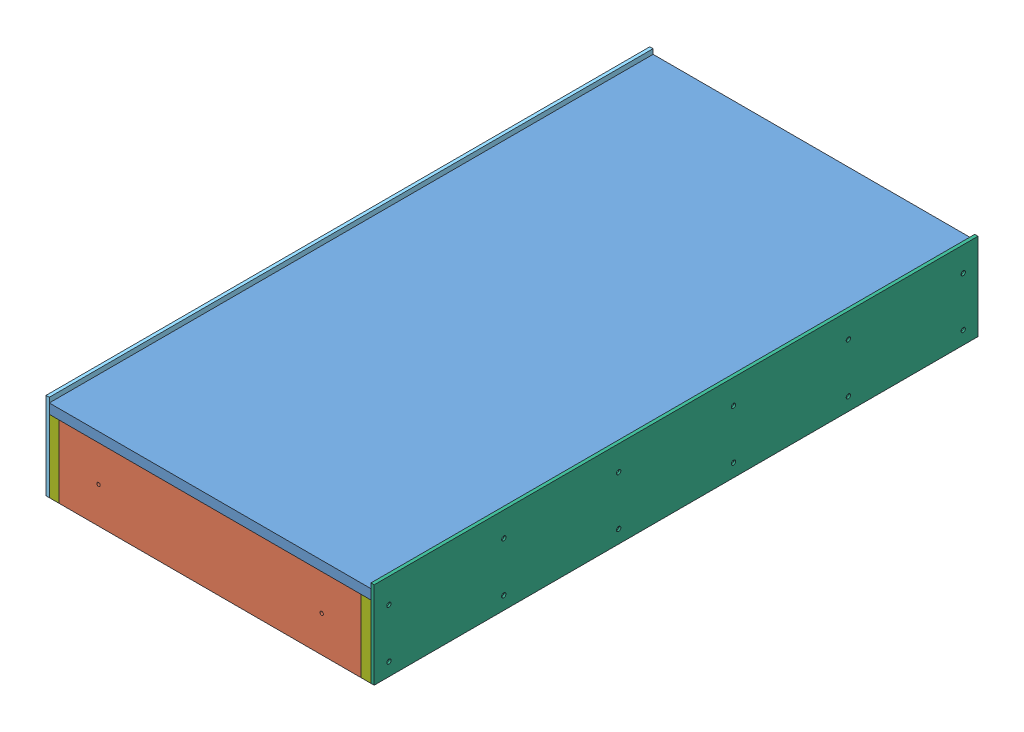
SolidWorks assembly GE-15014_ASM, configuration Default. Lengths in mm.
Overall size (635 168.27 1168.4).
9 component instances, 7 part files, 0 mates.
Components (placement in the parent):
- GE-15014-01-1: GE-15014-01 [Default] at origin size (622.3 19.05 1168.4)
- GE-15014-02_AF1-1: GE-15014-02_AF1 [Default] at (-292.1 -139.7 584.2) size (584.2 139.7 19.05)
- GE-15014-02-1: GE-15014-02 [Default] at (-292.1 -139.7 201.0833) size (584.2 139.7 19.05)
- GE-15014-02-2: GE-15014-02 [Default] at (-292.1 -139.7 -182.0333) size (584.2 139.7 19.05)
- GE-15014-02_AF0-1: GE-15014-02_AF0 [Default] at (-292.1 -139.7 -565.15) size (584.2 139.7 19.05)
- GE-15015-1: GE-15015 [Default] at (-317.5 -139.7 584.2) size (6.35 168.28 1168.4)
- GE-15016-1: GE-15016 [Default] at (311.15 -139.7 584.2) size (6.35 168.28 1168.4)
- GE-15014-05-1: GE-15014-05 [Default] at (292.1 -139.7 584.2) x (0 0 -1) z (1 0 0) size (1168.4 139.7 19.05)
- GE-15014-05-2: GE-15014-05 [Default] at (-292.1 -139.7 -584.2) x (0 0 1) z (-1 0 0) size (1168.4 139.7 19.05)
